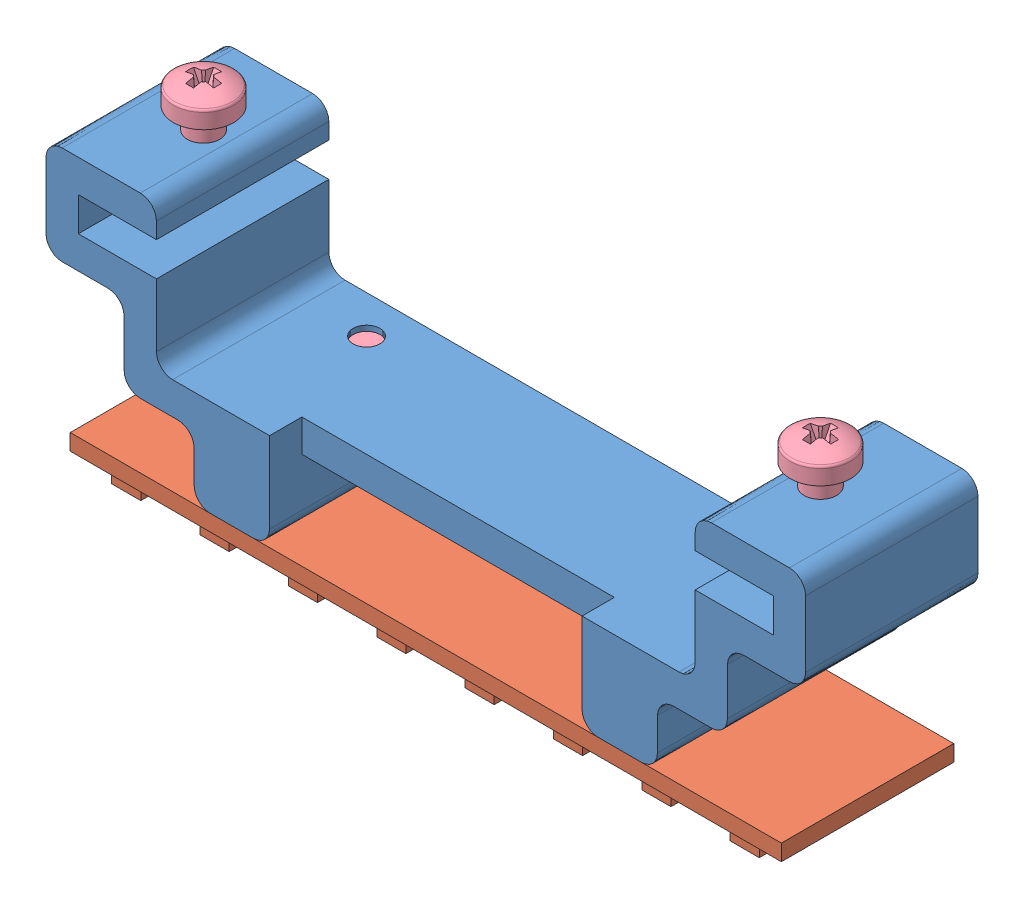
SolidWorks assembly Assembly schuiver QTR-8A, configuration Default. Lengths in mm.
Overall size (70.5 30.71 16).
7 component instances, 4 part files, 24 mates.
Components (placement in the parent):
- QTR-8A schuiver-1: QTR-8A schuiver [Default] at (0 0 -13.425) size (70.5 22.5 16)
- QTR-8A-1: QTR-8A [Default] at (0 -21 -5.425) x (1 0 0) z (0 0 -1) size (66 3.1 16)
- Header11P90-1: Header11P90 [Default] at (-12.7 -22.46 -12.155) x (0 0 1) z (0 1 0) size (8.45 27.94 7.3)
- pan head cross recess screw_iso-1: pan head cross recess screw_iso [ISO 7045 - M3 x 10 - Z - 10N] at (18 -23.4 -9.925) x (0 1 0) z (1 0 0) size (12.35 5.6 5.6)
- pan head cross recess screw_iso-2: pan head cross recess screw_iso [ISO 7045 - M3 x 10 - Z - 10N] at (-18 -23.4 -9.925) x (0 1 0) z (1 0 0) size (12.35 5.6 5.6)
- pan head cross recess screw_iso-3: pan head cross recess screw_iso [ISO 7045 - M3 x 5 - Z - 5N] at (-28.625 7.4 -5.425) x (0 -1 0) z (0 0 1) size (7.35 5.6 5.6)
- pan head cross recess screw_iso-4: pan head cross recess screw_iso [ISO 7045 - M3 x 5 - Z - 5N] at (28.625 7.4 -5.425) x (0 -1 0) z (0 0 1) size (7.35 5.6 5.6)
Mates (geometry in assembly coordinates):
- Coincident1: coincident aligned: plane of QTR-8A schuiver-1 through (0 0 -13.425) normal (1 0 0)
- Coincident2: coincident aligned: plane of QTR-8A schuiver-1 through (0 0 -13.425) normal (0 1 0)
- Coincident3: coincident anti-aligned: plane of QTR-8A schuiver-1 through (21.5 -19.5 2.575) normal (0 -1 0); plane of QTR-8A-1 through (0 -19.5 -5.425) normal (0 1 0)
- Coincident4: coincident aligned: plane of QTR-8A schuiver-1 through (0 0 2.575) normal (0 0 1); plane of QTR-8A-1 through (-33 -19.5 2.575) normal (0 0 1)
- Coincident5: coincident aligned: plane of QTR-8A-1 through (0 -21 -5.425) normal (1 0 0)
- Coincident6: coincident: point of QTR-8A-1
- Coincident7: coincident aligned: plane of QTR-8A-1 through (-33 -19.5 -13.425) normal (0 0 -1); plane of Header11P90-1 through (13.97 -19.5 -13.425) normal (0 0 -1)
- Coincident8: coincident anti-aligned: plane of QTR-8A-1 through (0 -19.5 -5.425) normal (0 1 0); plane of Header11P90-1 through (11.43 -19.5 -12.925) normal (0 -1 0)
- Coincident9: coincident: unknown of Header11P90-1
- Coincident10: coincident aligned: plane of hex thin nut chamfered gradeab_iso-1 through (-19.5877 -21 -7.175) normal (0 1 0); plane of hex thin nut chamfered gradeab_iso-2 through (16.4123 -21 -7.175) normal (0 1 0)
- Concentric1: concentric anti-aligned: cylinder of QTR-8A-1 through (-18 -19.5 -9.925) axis (0 -1 0) radius 1.5; cylinder of hex thin nut chamfered gradeab_iso-1 through (-18 -22.8 -9.925) axis (0 1 0) radius 1.25
- Coincident11: coincident anti-aligned: plane of QTR-8A-1 through (0 -21 -5.425) normal (0 -1 0); plane of hex thin nut chamfered gradeab_iso-2 through (16.4123 -21 -7.175) normal (0 1 0)
- Concentric2: concentric aligned: cylinder of QTR-8A-1 through (18 -19.5 -9.925) axis (0 -1 0) radius 1.5; cylinder of hex thin nut chamfered gradeab_iso-2 through (18 -21 -9.925) axis (0 -1 0) radius 1.25
- Coincident12: coincident aligned: plane of hex thin nut chamfered gradeab_iso-1 through (-16.4123 -22.8 -12.675) normal (0 0 -1); plane of hex thin nut chamfered gradeab_iso-2 through (16.4123 -21 -12.675) normal (0 0 -1)
- Coincident13: coincident aligned: plane of pan head cross recess screw_iso-1 through (18 -21 -8.425) normal (0 1 0); plane of pan head cross recess screw_iso-2 through (-18 -21 -8.425) normal (0 1 0)
- Coincident14: coincident aligned: plane of pan head cross recess screw_iso-1 through (18.5275 -21.65 -9.555) normal (0 0 -1); plane of pan head cross recess screw_iso-2 through (-17.4725 -21.65 -9.555) normal (0 0 -1)
- Coincident15: coincident anti-aligned: plane of QTR-8A-1 through (0 -21 -5.425) normal (0 -1 0); plane of pan head cross recess screw_iso-2 through (-18 -21 -8.425) normal (0 1 0)
- Concentric3: concentric aligned: cylinder of QTR-8A-1 through (-18 -19.5 -9.925) axis (0 -1 0) radius 1.5; cylinder of pan head cross recess screw_iso-2 through (-18 -48.8 -9.925) axis (0 -1 0) radius 1.5
- Concentric4: concentric aligned: cylinder of QTR-8A-1 through (18 -19.5 -9.925) axis (0 -1 0) radius 1.5; cylinder of pan head cross recess screw_iso-1 through (18 -48.8 -9.925) axis (0 -1 0) radius 1.5
- Coincident16: coincident aligned: plane of pan head cross recess screw_iso-3 through (-27.125 0 -5.425) normal (0 -1 0); plane of pan head cross recess screw_iso-4 through (30.125 0 -5.425) normal (0 -1 0)
- Coincident17: coincident aligned: plane of QTR-8A schuiver-1 through (-25 0 2.575) normal (0 -1 0); plane of pan head cross recess screw_iso-3 through (-27.125 0 -5.425) normal (0 -1 0)
- Concentric5: concentric aligned: cylinder of QTR-8A schuiver-1 through (-28.625 -19.501 -5.425) axis (0 1 0) radius 1.25; cylinder of pan head cross recess screw_iso-3 through (-28.625 32.8 -5.425) axis (0 1 0) radius 1.5
- Concentric6: concentric aligned: cylinder of QTR-8A schuiver-1 through (28.625 -19.501 -5.425) axis (0 1 0) radius 1.25; cylinder of pan head cross recess screw_iso-4 through (28.625 32.8 -5.425) axis (0 1 0) radius 1.5
- Coincident18: coincident aligned: plane of pan head cross recess screw_iso-3 through (-28.0975 5.65 -5.795) normal (0 0 1); plane of pan head cross recess screw_iso-4 through (29.1525 5.65 -5.795) normal (0 0 1)
